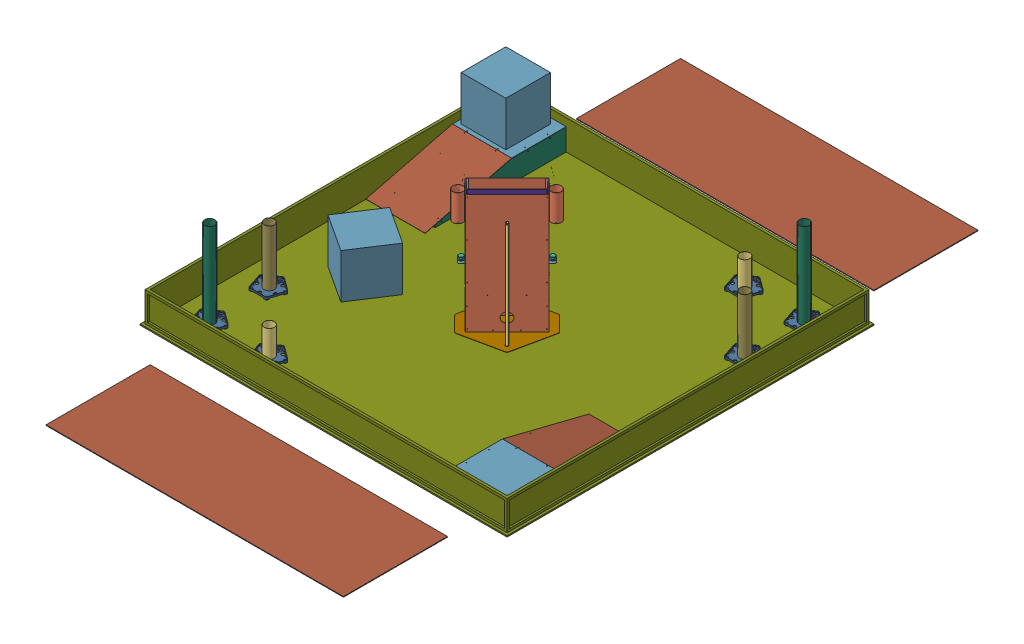
SolidWorks assembly FIELD, configuration Default. Lengths in mm.
Overall size (3759.2 1387.73 6502.4).
321 component instances, 51 part files, 0 mates.
Components (placement in the parent):
- pentagon_foot-1: pentagon_foot [Default] at (988.2301 6.35 -1420.0673) x (-0.309017 0 -0.951057) z (0.951057 0 -0.309017) size (62.1 10.92 43.36)
- 1in_ball_caster-1: 1in_ball_caster [Default] at (913.384 12.7 -1651.3697) x (-0.809017 0 0.587785) z (-0.587785 0 -0.809017) size (25.4 25.4 25.4)
- pentagon_foot-2: pentagon_foot [Default] at (1034.3923 6.35 -1562.3639) x (-1 0 0) z (0 0 -1) size (62.1 10.92 43.36)
- 1in_ball_caster-2: 1in_ball_caster [Default] at (791.2819 12.7 -1562.6574) x (0.309017 0 0.951057) z (-0.951057 0 0.309017) size (25.4 25.4 25.4)
- pentagon_foot-3: pentagon_foot [Default] at (913.3251 6.35 -1650.2388) x (-0.309017 0 0.951057) z (-0.951057 0 -0.309017) size (62.1 10.92 43.36)
- pipe_-_30cm-1: pipe_-_30cm [Default] at (913.384 25.4 -1522.984) size (103.63 274.6 103.63)
- boss-extrude10_2_-1: boss-extrude10_2_ [Default] at (913.384 12.7 -1522.984) size (18.23 0.25 19.26)
- boss-extrude10_3_-1: boss-extrude10_3_ [Default] at (913.384 12.7 -1522.984) size (18.74 0.25 19.26)
- boss-extrude10_5_-1: boss-extrude10_5_ [Default] at (913.384 12.7 -1522.984) size (15.54 0.29 7.33)
- boss-extrude10_7_-1: boss-extrude10_7_ [Default] at (913.384 12.7 -1522.984) size (2.53 0.25 2.49)
- boss-extrude10_1_-1: boss-extrude10_1_ [Default] at (913.384 12.7 -1522.984) size (20.84 0.25 21.41)
- boss-extrude10_6_-1: boss-extrude10_6_ [Default] at (913.384 12.7 -1522.984) size (1.07 0.25 1.44)
- boss-extrude11-1: boss-extrude11 [Default] at (913.384 12.7 -1522.984) size (286.32 38.24 275.93)
- pentagon_foot-4: pentagon_foot [Default] at (792.3393 6.35 -1562.2519) x (0.809017 0 0.587785) z (-0.587785 0 0.809017) size (62.1 10.92 43.36)
- pentagon_foot-5: pentagon_foot [Default] at (838.6332 6.35 -1419.9981) x (0.809017 0 -0.587785) z (0.587785 0 0.809017) size (62.1 10.92 43.36)
- 1in_ball_caster-3: 1in_ball_caster [Default] at (988.8472 12.7 -1419.1178) x (0.309017 0 -0.951057) z (0.951057 0 0.309017) size (25.4 25.4 25.4)
- 1in_ball_caster-4: 1in_ball_caster [Default] at (837.9208 12.7 -1419.1178) size (25.4 25.4 25.4)
- 1in_ball_caster-5: 1in_ball_caster [Default] at (1035.4861 12.7 -1562.6574) x (-0.809017 0 -0.587785) z (0.587785 0 -0.809017) size (25.4 25.4 25.4)
- player_station-1: player_station [Default] at (1574.8 -12.7 3251.2) x (0 0 -1) z (1 0 0) size (1066.8 6.35 3048)
- pentagon_foot-6: pentagon_foot [Default] at (-1401.9757 6.35 874.0041) x (-1 0 0) z (0 0 -1) size (62.1 10.92 43.36)
- 1in_ball_caster-6: 1in_ball_caster [Default] at (-1645.0861 12.7 873.7106) x (0.309017 0 0.951057) z (-0.951057 0 0.309017) size (25.4 25.4 25.4)
- pentagon_foot-7: pentagon_foot [Default] at (-1523.0429 6.35 786.1292) x (-0.309017 0 0.951057) z (-0.951057 0 -0.309017) size (62.1 10.92 43.36)
- pipe_-_60cm-1: pipe_-_60cm [Default] at (-1522.984 25.4 913.384) size (103.63 574.6 103.63)
- boss-extrude10_2_-2: boss-extrude10_2_ [Default] at (-1522.984 12.7 913.384) size (18.23 0.25 19.26)
- boss-extrude10_4_-2: boss-extrude10_4_ [Default] at (-1522.984 12.7 913.384) size (58.22 0.4 40.75)
- boss-extrude10_3_-2: boss-extrude10_3_ [Default] at (-1522.984 12.7 913.384) size (18.74 0.25 19.26)
- boss-extrude10_5_-2: boss-extrude10_5_ [Default] at (-1522.984 12.7 913.384) size (15.54 0.29 7.33)
- boss-extrude10_7_-2: boss-extrude10_7_ [Default] at (-1522.984 12.7 913.384) size (2.53 0.25 2.49)
- boss-extrude10_1_-2: boss-extrude10_1_ [Default] at (-1522.984 12.7 913.384) size (20.84 0.25 21.41)
- boss-extrude10_6_-2: boss-extrude10_6_ [Default] at (-1522.984 12.7 913.384) size (1.07 0.25 1.44)
- boss-extrude11-2: boss-extrude11 [Default] at (-1522.984 12.7 913.384) size (286.32 38.24 275.93)
- pentagon_foot-8: pentagon_foot [Default] at (-1644.0287 6.35 874.1161) x (0.809017 0 0.587785) z (-0.587785 0 0.809017) size (62.1 10.92 43.36)
- pentagon_foot-9: pentagon_foot [Default] at (-1597.7348 6.35 1016.3699) x (0.809017 0 -0.587785) z (0.587785 0 0.809017) size (62.1 10.92 43.36)
- 1in_ball_caster-7: 1in_ball_caster [Default] at (-1447.5208 12.7 1017.2502) x (0.309017 0 -0.951057) z (0.951057 0 0.309017) size (25.4 25.4 25.4)
- 1in_ball_caster-8: 1in_ball_caster [Default] at (-1598.4472 12.7 1017.2502) size (25.4 25.4 25.4)
- 1in_ball_caster-9: 1in_ball_caster [Default] at (-1400.8819 12.7 873.7106) x (-0.809017 0 -0.587785) z (0.587785 0 -0.809017) size (25.4 25.4 25.4)
- pentagon_foot-10: pentagon_foot [Default] at (-1448.1379 6.35 1016.3007) x (-0.309017 0 -0.951057) z (0.951057 0 -0.309017) size (62.1 10.92 43.36)
- 1in_ball_caster-10: 1in_ball_caster [Default] at (-1522.984 12.7 784.9983) x (-0.809017 0 0.587785) z (-0.587785 0 -0.809017) size (25.4 25.4 25.4)
- player_station-2: player_station [Default] at (-1473.2 -12.7 -3251.2) x (0 0 1) z (-1 0 0) size (1066.8 6.35 3048)
- pentagon_foot-11: pentagon_foot [Default] at (1643.9923 6.35 -952.7639) x (-1 0 0) z (0 0 -1) size (62.1 10.92 43.36)
- 1in_ball_caster-11: 1in_ball_caster [Default] at (1400.8819 12.7 -953.0574) x (0.309017 0 0.951057) z (-0.951057 0 0.309017) size (25.4 25.4 25.4)
- pentagon_foot-12: pentagon_foot [Default] at (1522.9251 6.35 -1040.6388) x (-0.309017 0 0.951057) z (-0.951057 0 -0.309017) size (62.1 10.92 43.36)
- pipe_-_60cm-2: pipe_-_60cm [Default] at (1522.984 25.4 -913.384) size (103.63 574.6 103.63)
- boss-extrude10_2_-3: boss-extrude10_2_ [Default] at (1522.984 12.7 -913.384) size (18.23 0.25 19.26)
- boss-extrude10_4_-3: boss-extrude10_4_ [Default] at (1522.984 12.7 -913.384) size (58.22 0.4 40.75)
- boss-extrude10_3_-3: boss-extrude10_3_ [Default] at (1522.984 12.7 -913.384) size (18.74 0.25 19.26)
- boss-extrude10_5_-3: boss-extrude10_5_ [Default] at (1522.984 12.7 -913.384) size (15.54 0.29 7.33)
- boss-extrude10_7_-3: boss-extrude10_7_ [Default] at (1522.984 12.7 -913.384) size (2.53 0.25 2.49)
- boss-extrude10_1_-3: boss-extrude10_1_ [Default] at (1522.984 12.7 -913.384) size (20.84 0.25 21.41)
- boss-extrude10_6_-3: boss-extrude10_6_ [Default] at (1522.984 12.7 -913.384) size (1.07 0.25 1.44)
- boss-extrude11-3: boss-extrude11 [Default] at (1522.984 12.7 -913.384) size (286.32 38.24 275.93)
- pentagon_foot-13: pentagon_foot [Default] at (1401.9393 6.35 -952.6519) x (0.809017 0 0.587785) z (-0.587785 0 0.809017) size (62.1 10.92 43.36)
- pentagon_foot-14: pentagon_foot [Default] at (1448.2332 6.35 -810.3981) x (0.809017 0 -0.587785) z (0.587785 0 0.809017) size (62.1 10.92 43.36)
- 1in_ball_caster-12: 1in_ball_caster [Default] at (1598.4472 12.7 -809.5178) x (0.309017 0 -0.951057) z (0.951057 0 0.309017) size (25.4 25.4 25.4)
- 1in_ball_caster-13: 1in_ball_caster [Default] at (1447.5208 12.7 -809.5178) size (25.4 25.4 25.4)
- 1in_ball_caster-14: 1in_ball_caster [Default] at (1645.0861 12.7 -953.0574) x (-0.809017 0 -0.587785) z (0.587785 0 -0.809017) size (25.4 25.4 25.4)
- pentagon_foot-15: pentagon_foot [Default] at (1597.8301 6.35 -810.4673) x (-0.309017 0 -0.951057) z (0.951057 0 -0.309017) size (62.1 10.92 43.36)
- 1in_ball_caster-15: 1in_ball_caster [Default] at (1522.984 12.7 -1041.7697) x (-0.809017 0 0.587785) z (-0.587785 0 -0.809017) size (25.4 25.4 25.4)
- simple_robot_starting_size-1: simple_robot_starting_size [Default] at (-1554.8184 225.25 -1542.4588) size (457.2 457.2 457.2)
- pentagon_foot-16: pentagon_foot [Default] at (-1523.0429 6.35 1395.7292) x (-0.309017 0 0.951057) z (-0.951057 0 -0.309017) size (62.1 10.92 43.36)
- pipe_-_90cm-1: pipe_-_90cm [Default] at (-1522.984 25.4 1522.984) size (103.63 874.6 103.63)
- boss-extrude10_2_-4: boss-extrude10_2_ [Default] at (-1522.984 12.7 1522.984) size (18.23 0.25 19.26)
- boss-extrude10_4_-4: boss-extrude10_4_ [Default] at (-1522.984 12.7 1522.984) size (58.22 0.4 40.75)
- boss-extrude10_3_-4: boss-extrude10_3_ [Default] at (-1522.984 12.7 1522.984) size (18.74 0.25 19.26)
- boss-extrude10_5_-4: boss-extrude10_5_ [Default] at (-1522.984 12.7 1522.984) size (15.54 0.29 7.33)
- boss-extrude10_7_-4: boss-extrude10_7_ [Default] at (-1522.984 12.7 1522.984) size (2.53 0.25 2.49)
- boss-extrude10_1_-4: boss-extrude10_1_ [Default] at (-1522.984 12.7 1522.984) size (20.84 0.25 21.41)
- boss-extrude10_6_-4: boss-extrude10_6_ [Default] at (-1522.984 12.7 1522.984) size (1.07 0.25 1.44)
- boss-extrude11-4: boss-extrude11 [Default] at (-1522.984 12.7 1522.984) size (286.32 38.24 275.93)
- pentagon_foot-17: pentagon_foot [Default] at (-1644.0287 6.35 1483.7161) x (0.809017 0 0.587785) z (-0.587785 0 0.809017) size (62.1 10.92 43.36)
- pentagon_foot-18: pentagon_foot [Default] at (-1597.7348 6.35 1625.9699) x (0.809017 0 -0.587785) z (0.587785 0 0.809017) size (62.1 10.92 43.36)
- 1in_ball_caster-16: 1in_ball_caster [Default] at (-1447.5208 12.7 1626.8502) x (0.309017 0 -0.951057) z (0.951057 0 0.309017) size (25.4 25.4 25.4)
- 1in_ball_caster-17: 1in_ball_caster [Default] at (-1598.4472 12.7 1626.8502) size (25.4 25.4 25.4)
- 1in_ball_caster-18: 1in_ball_caster [Default] at (-1400.8819 12.7 1483.3106) x (-0.809017 0 -0.587785) z (0.587785 0 -0.809017) size (25.4 25.4 25.4)
- pentagon_foot-19: pentagon_foot [Default] at (-1448.1379 6.35 1625.9007) x (-0.309017 0 -0.951057) z (0.951057 0 -0.309017) size (62.1 10.92 43.36)
- 1in_ball_caster-19: 1in_ball_caster [Default] at (-1522.984 12.7 1394.5983) x (-0.809017 0 0.587785) z (-0.587785 0 -0.809017) size (25.4 25.4 25.4)
- pentagon_foot-20: pentagon_foot [Default] at (-1401.9757 6.35 1483.6041) x (-1 0 0) z (0 0 -1) size (62.1 10.92 43.36)
- 1in_ball_caster-20: 1in_ball_caster [Default] at (-1645.0861 12.7 1483.3106) x (0.309017 0 0.951057) z (-0.951057 0 0.309017) size (25.4 25.4 25.4)
- field_marking_v2-1: field_marking_v2 [Default] at origin size (3759.2 317.5 3759.2)
- simple_robot_starting_size-2: simple_robot_starting_size [Default] at (-1302.6345 228.6 216.2201) x (0 -1 0) z (-0.546944 0 0.837169) size (457.2 457.2 457.2)
- pentagon_foot-21: pentagon_foot [Default] at (1522.9251 6.35 -1650.2388) x (-0.309017 0 0.951057) z (-0.951057 0 -0.309017) size (62.1 10.92 43.36)
- pipe_-_90cm-2: pipe_-_90cm [Default] at (1522.984 25.4 -1522.984) size (103.63 874.6 103.63)
- boss-extrude10_2_-5: boss-extrude10_2_ [Default] at (1522.984 12.7 -1522.984) size (18.23 0.25 19.26)
- boss-extrude10_4_-5: boss-extrude10_4_ [Default] at (1522.984 12.7 -1522.984) size (58.22 0.4 40.75)
- boss-extrude10_3_-5: boss-extrude10_3_ [Default] at (1522.984 12.7 -1522.984) size (18.74 0.25 19.26)
- boss-extrude10_5_-5: boss-extrude10_5_ [Default] at (1522.984 12.7 -1522.984) size (15.54 0.29 7.33)
- boss-extrude10_7_-5: boss-extrude10_7_ [Default] at (1522.984 12.7 -1522.984) size (2.53 0.25 2.49)
- boss-extrude10_1_-5: boss-extrude10_1_ [Default] at (1522.984 12.7 -1522.984) size (20.84 0.25 21.41)
- boss-extrude10_6_-5: boss-extrude10_6_ [Default] at (1522.984 12.7 -1522.984) size (1.07 0.25 1.44)
- boss-extrude11-5: boss-extrude11 [Default] at (1522.984 12.7 -1522.984) size (286.32 38.24 275.93)
- pentagon_foot-22: pentagon_foot [Default] at (1401.9393 6.35 -1562.2519) x (0.809017 0 0.587785) z (-0.587785 0 0.809017) size (62.1 10.92 43.36)
- pentagon_foot-23: pentagon_foot [Default] at (1448.2332 6.35 -1419.9981) x (0.809017 0 -0.587785) z (0.587785 0 0.809017) size (62.1 10.92 43.36)
- 1in_ball_caster-21: 1in_ball_caster [Default] at (1598.4472 12.7 -1419.1178) x (0.309017 0 -0.951057) z (0.951057 0 0.309017) size (25.4 25.4 25.4)
- 1in_ball_caster-22: 1in_ball_caster [Default] at (1447.5208 12.7 -1419.1178) size (25.4 25.4 25.4)
- 1in_ball_caster-23: 1in_ball_caster [Default] at (1645.0861 12.7 -1562.6574) x (-0.809017 0 -0.587785) z (0.587785 0 -0.809017) size (25.4 25.4 25.4)
- pentagon_foot-24: pentagon_foot [Default] at (1597.8301 6.35 -1420.0673) x (-0.309017 0 -0.951057) z (0.951057 0 -0.309017) size (62.1 10.92 43.36)
- 1in_ball_caster-24: 1in_ball_caster [Default] at (1522.984 12.7 -1651.3697) x (-0.809017 0 0.587785) z (-0.587785 0 -0.809017) size (25.4 25.4 25.4)
- pentagon_foot-25: pentagon_foot [Default] at (1643.9923 6.35 -1562.3639) x (-1 0 0) z (0 0 -1) size (62.1 10.92 43.36)
- 1in_ball_caster-25: 1in_ball_caster [Default] at (1400.8819 12.7 -1562.6574) x (0.309017 0 0.951057) z (-0.951057 0 0.309017) size (25.4 25.4 25.4)
- 10-32x1000_shcs_hx-shcs_0_19-32-1: 10-32x1000_shcs_hx-shcs_0_19-32 [Default] at (-227.9189 968.2 209.9584) x (0.707107 0 -0.707107) z (0.270008 -0.924225 0.270008) size (30.23 7.94 7.94)
- 0_125_rivet-1: 0_125_rivet [Default] at (-167.1495 340.4348 44.6588) x (-0.927593 -0.275814 -0.251989) z (0.120714 0.417045 -0.900834) size (7.15 10.43 6.43)
- 0_125_rivet-2: 0_125_rivet [Default] at (211.8083 17.986 -211.8083) x (0.421492 -0.802925 0.421492) z (0.567754 0.59608 0.567754) size (7.15 10.43 6.43)
- ug_bottom-1: ug_bottom [Default] at (252.1656 925.4006 -252.1656) x (0.707107 0 0.707107) z (-0.707107 0 0.707107) size (101.6 12 101.6)
- 0_125_rivet-3: 0_125_rivet [Default] at (205.8442 1234.9 -223.8048) x (0.342629 0.874764 0.342629) z (-0.618551 0.48455 -0.618551) size (7.15 10.43 6.43)
- pipe_-_30cm_center_goal-1: pipe_-_30cm_center_goal [Default] at (252.1656 925.4006 -252.1656) x (0.707107 0 -0.707107) z (0.707107 0 0.707107) size (103.63 274.6 103.63)
- 0_125_rivet-4: 0_125_rivet [Default] at (223.8048 1234.9 -205.8442) x (0.342629 0.874764 0.342629) z (-0.618551 0.48455 -0.618551) size (7.15 10.43 6.43)
- curved_backboard_formed-1: curved_backboard_formed [Default] at (252.1656 1171.425 -252.1656) x (0.707107 0 0.707107) z (-0.707107 0 0.707107) size (90.88 168.28 49.85)
- 0_125_rivet-5: 0_125_rivet [Default] at (285.0872 931.4006 -219.244) x (-0.342629 0.874764 0.342629) z (0.618551 0.48455 -0.618551) size (7.15 10.43 6.43)
- backboard_clip_spacer-1: backboard_clip_spacer [Default] at (216.2446 1234.9 -216.2446) x (0.707107 0 0.707107) z (-0.707107 0 0.707107) size (50.8 25.4 6)
- 0_125_rivet-6: 0_125_rivet [Default] at (219.244 931.4006 -285.0872) x (-0.07956 -0.99365 0.07956) z (0.702617 -0.112515 -0.702617) size (7.15 10.43 6.43)
- backboard_clip-1: backboard_clip [Default] at (212.0019 1222.2 -212.0019) x (0.707107 0 0.707107) z (-0.707107 0 0.707107) size (50.8 50.8 6)
- 0_125_rivet-7: 0_125_rivet [Default] at (-274.5444 1196.8 134.0573) x (-0.103977 -0.98913 0.103977) z (0.69942 -0.147045 -0.69942) size (7.15 10.43 6.43)
- cut-revolve4-26359-1: cut-revolve4-26359 [Default] at (-10.5967 5.286 133.0874) x (-0.707107 0 0.707107) z (-0.707107 0 -0.707107) size (9.53 4.54 11)
- revolve2-28113-1: revolve2-28113 [Default] at (-10.5967 5.286 133.0874) x (-0.707107 0 0.707107) z (-0.707107 0 -0.707107) size (9.57 0.43 9.57)
- bracket_90_-_bolt_bottom-1: bracket_90_-_bolt_bottom [Default] at (8.9803 30.686 134.7038) x (0 -1 0) z (0.707107 0 -0.707107) size (27.69 27.69 25.4)
- floor_plate-1: floor_plate [Default] x (-0.707107 0 0.707107) z (-0.707107 0 -0.707107) size (762 3 713.05)
- 0_125_rivet-8: 0_125_rivet [Default] at (211.8083 453.85 -211.8083) x (-0.568301 -0.595036 -0.568301) z (0.420754 -0.803699 0.420754) size (7.15 10.43 6.43)
- 10-32_x_0_375_bhcs-1: 10-32_x_0_375_bhcs [Default] at (133.0874 0 -10.5967) x (-0.978716 0 0.20522) z (0.20522 0 0.978716) size (9.17 12.09 9.17)
- 0_125_rivet-9: 0_125_rivet [Default] at (134.0573 28.4 -274.5444) x (-0.171866 0.970012 0.171866) z (-0.685902 -0.243056 0.685902) size (7.15 10.43 6.43)
- 0_125_rivet-10: 0_125_rivet [Default] at (-1.5985 17.986 142.0856) x (0.171866 0.970012 -0.171866) z (0.685902 -0.243056 -0.685902) size (7.15 10.43 6.43)
- center_pivot_plate-1: center_pivot_plate [Default] at (0 -16.97 0) x (-0.707107 0 0.707107) z (-0.707107 0 -0.707107) size (152.4 3 152.4)
- 0_125_rivet-11: 0_125_rivet [Default] at (-211.8083 428.45 211.8083) x (-0.171866 -0.970012 -0.171866) z (-0.685902 0.243056 -0.685902) size (7.15 10.43 6.43)
- cut-revolve4-26359-2: cut-revolve4-26359 [Default] at (200.6868 5.286 -200.6868) x (-0.707107 0 0.707107) z (-0.707107 0 -0.707107) size (9.53 4.54 11)
- revolve2-28113-2: revolve2-28113 [Default] at (200.6868 5.286 -200.6868) x (-0.707107 0 0.707107) z (-0.707107 0 -0.707107) size (9.57 0.43 9.57)
- bracket_90-1: bracket_90 [Default] at (-31.7884 309.4652 175.4725) x (-0.353553 0.866025 0.353553) z (-0.612372 -0.5 0.612372) size (27.69 27.69 25.4)
- 0_125_rivet-12: 0_125_rivet [Default] at (274.5444 441.15 -134.0573) x (-0.421492 -0.802925 0.421492) z (-0.567754 0.59608 0.567754) size (7.15 10.43 6.43)
- 10-32x1250_shcs-1: 10-32x1250_shcs [Default] at (209.9225 968.2 -227.883) x (0 1 0) z (-0.707107 0 -0.707107) size (7.82 36.53 7.82)
- 0_125_rivet-13: 0_125_rivet [Default] at (44.6588 340.4348 -167.1495) x (0.765875 -0.485006 -0.422143) z (0.537062 0.121528 0.834743) size (7.15 10.43 6.43)
- 0_125_rivet-14: 0_125_rivet [Default] at (30.0998 326.8138 -170.587) x (-0.171866 0.970012 0.171866) z (-0.685902 -0.243056 0.685902) size (7.15 10.43 6.43)
- 0_125_rivet-15: 0_125_rivet [Default] at (-211.8083 238.5265 211.8083) x (0.171866 0.970012 0.171866) z (0.685902 -0.243056 0.685902) size (7.15 10.43 6.43)
- 0_125_rivet-16: 0_125_rivet [Default] at (-202.8281 1171.4 220.7886) x (-0.171866 -0.970012 -0.171866) z (-0.685902 0.243056 -0.685902) size (7.15 10.43 6.43)
- bracket_90_-_bolt_bottom-2: bracket_90_-_bolt_bottom [Default] at (-8.9803 30.686 -134.7038) x (0 -1 0) z (-0.707107 0 0.707107) size (27.69 27.69 25.4)
- splitter_ramp_v2-1: splitter_ramp_v2 [Default] at (0 3 0) x (0.707107 0 -0.707107) z (0.707107 0 0.707107) size (609.6 428.43 203.2)
- cut-revolve4-26359-3: cut-revolve4-26359 [Default] at (188.6971 968.2 -206.6576) x (-0.653525 -0.381849 -0.653525) z (-0.270008 0.924225 -0.270008) size (9.53 4.54 11)
- revolve2-28113-3: revolve2-28113 [Default] at (188.6971 968.2 -206.6576) x (-0.653525 -0.381849 -0.653525) z (-0.270008 0.924225 -0.270008) size (9.57 0.43 9.57)
- 0_125_rivet-17: 0_125_rivet [Default] at (134.0573 441.15 -274.5444) x (-0.171866 0.970012 0.171866) z (-0.685902 -0.243056 0.685902) size (7.15 10.43 6.43)
- 10-32_x_0_375_bhcs-2: 10-32_x_0_375_bhcs [Default] at (200.6868 0 -200.6868) x (-0.978716 0 0.20522) z (0.20522 0 0.978716) size (9.17 12.09 9.17)
- 0_125_rivet-18: 0_125_rivet [Default] at (134.0573 231.6 -274.5444) x (-0.171866 0.970012 0.171866) z (-0.685902 -0.243056 0.685902) size (7.15 10.43 6.43)
- 0_125_rivet-19: 0_125_rivet [Default] at (1.5985 17.986 -142.0856) x (-0.171866 0.970012 0.171866) z (-0.685902 -0.243056 0.685902) size (7.15 10.43 6.43)
- elevator_screw_1_25in-1: elevator_screw_1_25in [Default] at (0 -19.4592 0) x (-0.707107 0 0.707107) z (-0.707107 0 -0.707107) size (25.6 31.75 25.6)
- 0_125_rivet-20: 0_125_rivet [Default] at (-211.8083 453.85 211.8083) x (-0.171866 -0.970012 -0.171866) z (-0.685902 0.243056 -0.685902) size (7.15 10.43 6.43)
- cut-revolve4-26359-4: cut-revolve4-26359 [Default] at (-200.6868 5.286 200.6868) x (-0.707107 0 0.707107) z (-0.707107 0 -0.707107) size (9.53 4.54 11)
- revolve2-28113-4: revolve2-28113 [Default] at (-200.6868 5.286 200.6868) x (-0.707107 0 0.707107) z (-0.707107 0 -0.707107) size (9.57 0.43 9.57)
- bracket_90-2: bracket_90 [Default] at (-159.9182 322.1652 16.2341) x (-0.353553 0.866025 0.353553) z (0.612372 0.5 -0.612372) size (27.69 27.69 25.4)
- pipe_diverter-1: pipe_diverter [Default] at (202.3033 333.2 -202.3033) x (-0.707107 0 0.707107) z (-0.707107 0 -0.707107) size (25.4 266.7 25.4)
- 0_125_rivet-21: 0_125_rivet [Default] at (-134.0573 441.15 274.5444) x (0.171866 0.970012 -0.171866) z (0.685902 -0.243056 -0.685902) size (7.15 10.43 6.43)
- 10-32x1000_shcs_hx-shcs_0_19-32-2: 10-32x1000_shcs_hx-shcs_0_19-32 [Default] at (227.9189 968.2 -209.9584) x (-0.707107 0 0.707107) z (-0.707107 0 -0.707107) size (30.23 7.94 7.94)
- 0_125_rivet-22: 0_125_rivet [Default] at (167.1495 340.4348 -44.6588) x (0.765875 -0.485006 -0.422143) z (0.537062 0.121528 0.834743) size (7.15 10.43 6.43)
- 0_125_rivet-23: 0_125_rivet [Default] at (-170.587 326.8138 30.0998) x (-0.171866 0.970012 0.171866) z (-0.685902 -0.243056 0.685902) size (7.15 10.43 6.43)
- 0_125_rivet-24: 0_125_rivet [Default] at (-211.8083 225.8265 211.8083) x (0.171866 0.970012 0.171866) z (0.685902 -0.243056 0.685902) size (7.15 10.43 6.43)
- 0_125_rivet-25: 0_125_rivet [Default] at (-202.8281 866.6 220.7886) x (-0.171866 -0.970012 -0.171866) z (-0.685902 0.243056 -0.685902) size (7.15 10.43 6.43)
- bracket_90_-_bolt_bottom-3: bracket_90_-_bolt_bottom [Default] at (-152.6644 30.686 8.9803) x (0 -1 0) z (-0.707107 0 0.707107) size (27.69 27.69 25.4)
- upper_cross_brace-1: upper_cross_brace [Default] at (-2.1213 1019 2.1213) x (0.707107 0 -0.707107) z (-0.707107 0 -0.707107) size (597.6 355.6 44.8)
- cut-revolve4-26359-5: cut-revolve4-26359 [Default] at (-210.9243 968.2 192.9638) x (0.653525 0.381849 0.653525) z (-0.270008 0.924225 -0.270008) size (9.53 4.54 11)
- revolve2-28113-5: revolve2-28113 [Default] at (-210.9243 968.2 192.9638) x (0.653525 0.381849 0.653525) z (-0.270008 0.924225 -0.270008) size (9.57 0.43 9.57)
- 0_125_rivet-26: 0_125_rivet [Default] at (134.0573 818.975 -274.5444) x (-0.171866 0.970012 0.171866) z (-0.685902 -0.243056 0.685902) size (7.15 10.43 6.43)
- 10-32_x_0_375_bhcs-3: 10-32_x_0_375_bhcs [Default] at (10.5967 0 -133.0874) x (-0.978716 0 0.20522) z (0.20522 0 0.978716) size (9.17 12.09 9.17)
- 0_125_rivet-27: 0_125_rivet [Default] at (211.8083 238.5265 -211.8083) x (-0.568301 -0.595036 -0.568301) z (0.420754 -0.803699 0.420754) size (7.15 10.43 6.43)
- 0_125_rivet-28: 0_125_rivet [Default] at (-142.0856 17.986 1.5985) x (-0.171866 0.970012 0.171866) z (-0.685902 -0.243056 0.685902) size (7.15 10.43 6.43)
- revolve2-15193-1: revolve2-15193 [Default] at (0 3 0) x (-0.707107 0 0.707107) z (-0.707107 0 -0.707107) size (11.24 0.56 11.25)
- cut-revolve4-44804-1: cut-revolve4-44804 [Default] at (0 3 0) x (-0.707107 0 0.707107) z (-0.707107 0 -0.707107) size (11.11 5.35 12.83)
- 0_125_rivet-29: 0_125_rivet [Default] at (-211.8083 441.15 211.8083) x (-0.171866 -0.970012 -0.171866) z (-0.685902 0.243056 -0.685902) size (7.15 10.43 6.43)
- cut-revolve4-26359-6: cut-revolve4-26359 [Default] at (10.5967 5.286 -133.0874) x (-0.707107 0 0.707107) z (-0.707107 0 -0.707107) size (9.53 4.54 11)
- revolve2-28113-6: revolve2-28113 [Default] at (10.5967 5.286 -133.0874) x (-0.707107 0 0.707107) z (-0.707107 0 -0.707107) size (9.57 0.43 9.57)
- bracket_90-3: bracket_90 [Default] at (31.7884 309.4652 -175.4725) x (0.353553 0.866025 -0.353553) z (0.612372 -0.5 -0.612372) size (27.69 27.69 25.4)
- pipe_diverter-2: pipe_diverter [Default] at (-202.3033 333.2 202.3033) x (0.707107 0 -0.707107) z (0.707107 0 0.707107) size (25.4 266.7 25.4)
- 0_125_rivet-30: 0_125_rivet [Default] at (-134.0573 818.975 274.5444) x (0.171866 0.970012 -0.171866) z (0.685902 -0.243056 -0.685902) size (7.15 10.43 6.43)
- 10-32x1250_shcs-2: 10-32x1250_shcs [Default] at (-209.9225 968.2 227.883) x (0.653525 0.381849 0.653525) z (0.270008 -0.924225 0.270008) size (7.82 36.53 7.82)
- 0_125_rivet-31: 0_125_rivet [Default] at (-44.6588 340.4348 167.1495) x (-0.927593 -0.275814 -0.251989) z (0.120714 0.417045 -0.900834) size (7.15 10.43 6.43)
- 0_125_rivet-32: 0_125_rivet [Default] at (-30.0998 326.8138 170.587) x (0.421492 0.802925 -0.421492) z (0.567754 -0.59608 -0.567754) size (7.15 10.43 6.43)
- 0_125_rivet-33: 0_125_rivet [Default] at (-211.8083 213.1265 211.8083) x (0.171866 0.970012 0.171866) z (0.685902 -0.243056 0.685902) size (7.15 10.43 6.43)
- 0_125_rivet-34: 0_125_rivet [Default] at (202.8281 1171.4 -220.7886) x (-0.568301 -0.595036 -0.568301) z (0.420754 -0.803699 0.420754) size (7.15 10.43 6.43)
- bracket_90_-_bolt_bottom-4: bracket_90_-_bolt_bottom [Default] at (152.6644 30.686 -8.9803) x (0 -1 0) z (0.707107 0 -0.707107) size (27.69 27.69 25.4)
- front_panel_v2-1: front_panel_v2 [Default] at (73.9614 612.6 73.9614) x (-0.707107 0 0.707107) z (-0.707107 0 -0.707107) size (604.84 1219.2 3)
- cut-revolve4-26359-7: cut-revolve4-26359 [Default] at (-188.6971 968.2 206.6576) x (0.653525 0.381849 0.653525) z (-0.270008 0.924225 -0.270008) size (9.53 4.54 11)
- revolve2-28113-7: revolve2-28113 [Default] at (-188.6971 968.2 206.6576) x (0.653525 0.381849 0.653525) z (-0.270008 0.924225 -0.270008) size (9.57 0.43 9.57)
- 0_125_rivet-35: 0_125_rivet [Default] at (134.0573 1196.8 -274.5444) x (-0.171866 0.970012 0.171866) z (-0.685902 -0.243056 0.685902) size (7.15 10.43 6.43)
- 10-32_x_0_375_bhcs-4: 10-32_x_0_375_bhcs [Default] at (-133.0874 0 10.5967) x (-0.978716 0 0.20522) z (0.20522 0 0.978716) size (9.17 12.09 9.17)
- 0_125_rivet-36: 0_125_rivet [Default] at (211.8083 225.8265 -211.8083) x (-0.568301 -0.595036 -0.568301) z (0.420754 -0.803699 0.420754) size (7.15 10.43 6.43)
- 0_125_rivet-37: 0_125_rivet [Default] at (274.5444 28.4 -134.0573) x (-0.421492 -0.802925 0.421492) z (-0.567754 0.59608 0.567754) size (7.15 10.43 6.43)
- pipe_v4-1: pipe_v4 [Default] at (134.5565 482.9183 134.5565) x (0.697656 0.162946 0.697656) z (-0.707107 0 0.707107) size (25.4 974.72 25.4)
- 0_125_rivet-38: 0_125_rivet [Default] at (-274.5444 441.15 134.0573) x (-0.103977 -0.98913 0.103977) z (0.69942 -0.147045 -0.69942) size (7.15 10.43 6.43)
- cut-revolve4-26359-8: cut-revolve4-26359 [Default] at (-133.0874 5.286 10.5967) x (-0.707107 0 0.707107) z (-0.707107 0 -0.707107) size (9.53 4.54 11)
- revolve2-28113-8: revolve2-28113 [Default] at (-133.0874 5.286 10.5967) x (-0.707107 0 0.707107) z (-0.707107 0 -0.707107) size (9.57 0.43 9.57)
- bracket_90_-_bolt_bottom-5: bracket_90_-_bolt_bottom [Default] at (-202.3033 30.686 220.2638) x (0 -1 0) z (0.707107 0 0.707107) size (27.69 27.69 25.4)
- side_panel_upper-1: side_panel_upper [Default] at (211.2835 612.6 -211.2835) x (-0.707107 0 -0.707107) z (0.707107 0 -0.707107) size (203.2 806.45 25.4)
- 0_125_rivet-39: 0_125_rivet [Default] at (-134.0573 1196.8 274.5444) x (0.171866 0.970012 -0.171866) z (0.685902 -0.243056 -0.685902) size (7.15 10.43 6.43)
- new_irbeacon_base-1: new_irbeacon_base [Default] at (-234.8899 582.6125 234.8899) x (0.707107 0 0.707107) z (0 1 0) size (68.63 60.17 23.81)
- new_irbeacon_top-1: new_irbeacon_top [Default] at (-234.8899 582.6125 234.8899) x (0.707107 0 0.707107) z (0 1 0) size (68.35 60.04 25.42)
- 0_125_rivet-40: 0_125_rivet [Default] at (211.8083 428.45 -211.8083) x (-0.568301 -0.595036 -0.568301) z (0.420754 -0.803699 0.420754) size (7.15 10.43 6.43)
- 0_125_rivet-41: 0_125_rivet [Default] at (170.587 326.8138 -30.0998) x (0.421492 0.802925 -0.421492) z (0.567754 -0.59608 -0.567754) size (7.15 10.43 6.43)
- 0_125_rivet-42: 0_125_rivet [Default] at (-274.5444 231.6 134.0573) x (-0.171866 0.970012 0.171866) z (-0.685902 -0.243056 0.685902) size (7.15 10.43 6.43)
- 0_125_rivet-43: 0_125_rivet [Default] at (202.8281 866.6 -220.7886) x (-0.568301 -0.595036 -0.568301) z (0.420754 -0.803699 0.420754) size (7.15 10.43 6.43)
- ball_tray_v4-1: ball_tray_v4 [Default] at (-37.1563 968.2 -32.8897) x (-0.707107 0 0.707107) z (-0.707107 0 -0.707107) size (590.55 12 115.57)
- 0_125_rivet-44: 0_125_rivet [Default] at (-134.0573 28.4 274.5444) x (-0.421492 -0.802925 0.421492) z (-0.567754 0.59608 0.567754) size (7.15 10.43 6.43)
- front_panel_v2-2: front_panel_v2 [Default] at (-71.842 612.6 -71.842) x (-0.707107 0 0.707107) z (-0.707107 0 -0.707107) size (604.84 1219.2 3)
- cut-revolve4-26359-9: cut-revolve4-26359 [Default] at (210.9243 968.2 -192.9638) x (-0.653525 -0.381849 -0.653525) z (-0.270008 0.924225 -0.270008) size (9.53 4.54 11)
- revolve2-28113-9: revolve2-28113 [Default] at (210.9243 968.2 -192.9638) x (-0.653525 -0.381849 -0.653525) z (-0.270008 0.924225 -0.270008) size (9.57 0.43 9.57)
- 0_125_rivet-45: 0_125_rivet [Default] at (274.5444 1196.8 -134.0573) x (-0.421492 -0.802925 0.421492) z (-0.567754 0.59608 0.567754) size (7.15 10.43 6.43)
- 10-32_x_0_375_bhcs-5: 10-32_x_0_375_bhcs [Default] at (-200.6868 0 200.6868) x (-0.978716 0 0.20522) z (0.20522 0 0.978716) size (9.17 12.09 9.17)
- 0_125_rivet-46: 0_125_rivet [Default] at (211.8083 213.1265 -211.8083) x (-0.568301 -0.595036 -0.568301) z (0.420754 -0.803699 0.420754) size (7.15 10.43 6.43)
- 0_125_rivet-47: 0_125_rivet [Default] at (274.5444 231.6 -134.0573) x (-0.421492 -0.802925 0.421492) z (-0.567754 0.59608 0.567754) size (7.15 10.43 6.43)
- ug_bottom-2: ug_bottom [Default] at (-252.1656 925.4006 252.1656) x (-0.707107 0 -0.707107) z (0.707107 0 -0.707107) size (101.6 12 101.6)
- 0_125_rivet-48: 0_125_rivet [Default] at (-205.8442 1234.9 223.8048) x (-0.342629 0.874764 -0.342629) z (0.618551 0.48455 0.618551) size (7.15 10.43 6.43)
- pipe_-_30cm_center_goal-2: pipe_-_30cm_center_goal [Default] at (-252.1656 925.4006 252.1656) x (-0.707107 0 0.707107) z (-0.707107 0 -0.707107) size (103.63 274.6 103.63)
- 0_125_rivet-49: 0_125_rivet [Default] at (-223.8048 1234.9 205.8442) x (-0.342629 0.874764 -0.342629) z (0.618551 0.48455 0.618551) size (7.15 10.43 6.43)
- curved_backboard_formed-2: curved_backboard_formed [Default] at (-252.1656 1171.425 252.1656) x (-0.707107 0 -0.707107) z (0.707107 0 -0.707107) size (90.88 168.28 49.85)
- 0_125_rivet-50: 0_125_rivet [Default] at (-285.0872 931.4006 219.244) x (0.342629 0.874764 -0.342629) z (-0.618551 0.48455 0.618551) size (7.15 10.43 6.43)
- backboard_clip_spacer-2: backboard_clip_spacer [Default] at (-216.2446 1234.9 216.2446) x (-0.707107 0 -0.707107) z (0.707107 0 -0.707107) size (50.8 25.4 6)
- 0_125_rivet-51: 0_125_rivet [Default] at (-219.244 931.4006 285.0872) x (0.07956 -0.99365 -0.07956) z (-0.702617 -0.112515 0.702617) size (7.15 10.43 6.43)
- backboard_clip-2: backboard_clip [Default] at (-212.0019 1222.2 212.0019) x (-0.707107 0 -0.707107) z (0.707107 0 -0.707107) size (50.8 50.8 6)
- 0_125_rivet-52: 0_125_rivet [Default] at (-274.5444 818.975 134.0573) x (-0.103977 -0.98913 0.103977) z (0.69942 -0.147045 -0.69942) size (7.15 10.43 6.43)
- cut-revolve4-26359-10: cut-revolve4-26359 [Default] at (133.0874 5.286 -10.5967) x (-0.707107 0 0.707107) z (-0.707107 0 -0.707107) size (9.53 4.54 11)
- revolve2-28113-10: revolve2-28113 [Default] at (133.0874 5.286 -10.5967) x (-0.707107 0 0.707107) z (-0.707107 0 -0.707107) size (9.57 0.43 9.57)
- bracket_90_-_bolt_bottom-6: bracket_90_-_bolt_bottom [Default] at (202.3033 30.686 -220.2638) x (0 -1 0) z (-0.707107 0 -0.707107) size (27.69 27.69 25.4)
- side_panel_upper-2: side_panel_upper [Default] at (-211.2835 612.6 211.2835) x (0.707107 0 0.707107) z (-0.707107 0 0.707107) size (203.2 806.45 25.4)
- 0_125_rivet-53: 0_125_rivet [Default] at (-134.0573 231.6 274.5444) x (-0.421492 -0.802925 0.421492) z (-0.567754 0.59608 0.567754) size (7.15 10.43 6.43)
- new_irbeacon_base-2: new_irbeacon_base [Default] at (234.8899 582.6125 -234.8899) x (-0.707107 0 -0.707107) z (0 1 0) size (68.63 60.17 23.81)
- new_irbeacon_top-2: new_irbeacon_top [Default] at (234.8899 582.6125 -234.8899) x (-0.707107 0 -0.707107) z (0 1 0) size (68.35 60.04 25.42)
- 0_125_rivet-54: 0_125_rivet [Default] at (211.8083 441.15 -211.8083) x (-0.568301 -0.595036 -0.568301) z (0.420754 -0.803699 0.420754) size (7.15 10.43 6.43)
- 10-32_x_0_375_bhcs-6: 10-32_x_0_375_bhcs [Default] at (-10.5967 0 133.0874) x (-0.978716 0 0.20522) z (0.20522 0 0.978716) size (9.17 12.09 9.17)
- 0_125_rivet-55: 0_125_rivet [Default] at (-274.5444 28.4 134.0573) x (-0.171866 0.970012 0.171866) z (-0.685902 -0.243056 0.685902) size (7.15 10.43 6.43)
- 0_125_rivet-56: 0_125_rivet [Default] at (142.0856 17.986 -1.5985) x (0.171866 0.970012 -0.171866) z (0.685902 -0.243056 -0.685902) size (7.15 10.43 6.43)
- pipe_v4-2: pipe_v4 [Default] at (-134.8712 482.9798 -134.8712) x (0.697762 -0.162036 0.697762) z (-0.707107 0 0.707107) size (25.4 974.72 25.4)
- 0_125_rivet-57: 0_125_rivet [Default] at (-211.8083 17.986 211.8083) x (0.171866 0.970012 0.171866) z (0.685902 -0.243056 0.685902) size (7.15 10.43 6.43)
- ball_tray_v4-2: ball_tray_v4 [Default] at (37.1563 968.2 32.8897) x (0.707107 0 -0.707107) z (0.707107 0 0.707107) size (590.55 12 115.57)
- bracket_90-4: bracket_90 [Default] at (159.9182 322.1652 -16.2341) x (0.353553 0.866025 -0.353553) z (-0.612372 0.5 0.612372) size (27.69 27.69 25.4)
- 0_125_rivet-58: 0_125_rivet [Default] at (274.5444 818.975 -134.0573) x (-0.421492 -0.802925 0.421492) z (-0.567754 0.59608 0.567754) size (7.15 10.43 6.43)
- pentagon_foot-26: pentagon_foot [Default] at (-838.5379 6.35 1625.9007) x (-0.309017 0 -0.951057) z (0.951057 0 -0.309017) size (62.1 10.92 43.36)
- 1in_ball_caster-26: 1in_ball_caster [Default] at (-913.384 12.7 1394.5983) x (-0.809017 0 0.587785) z (-0.587785 0 -0.809017) size (25.4 25.4 25.4)
- pentagon_foot-27: pentagon_foot [Default] at (-792.3757 6.35 1483.6041) x (-1 0 0) z (0 0 -1) size (62.1 10.92 43.36)
- 1in_ball_caster-27: 1in_ball_caster [Default] at (-1035.4861 12.7 1483.3106) x (0.309017 0 0.951057) z (-0.951057 0 0.309017) size (25.4 25.4 25.4)
- pentagon_foot-28: pentagon_foot [Default] at (-913.4429 6.35 1395.7292) x (-0.309017 0 0.951057) z (-0.951057 0 -0.309017) size (62.1 10.92 43.36)
- pipe_-_30cm-2: pipe_-_30cm [Default] at (-913.384 25.4 1522.984) size (103.63 274.6 103.63)
- boss-extrude10_2_-6: boss-extrude10_2_ [Default] at (-913.384 12.7 1522.984) size (18.23 0.25 19.26)
- boss-extrude10_4_-6: boss-extrude10_4_ [Default] at (-913.384 12.7 1522.984) size (58.22 0.4 40.75)
- boss-extrude10_3_-6: boss-extrude10_3_ [Default] at (-913.384 12.7 1522.984) size (18.74 0.25 19.26)
- boss-extrude10_5_-6: boss-extrude10_5_ [Default] at (-913.384 12.7 1522.984) size (15.54 0.29 7.33)
- boss-extrude10_7_-6: boss-extrude10_7_ [Default] at (-913.384 12.7 1522.984) size (2.53 0.25 2.49)
- boss-extrude10_1_-6: boss-extrude10_1_ [Default] at (-913.384 12.7 1522.984) size (20.84 0.25 21.41)
- boss-extrude10_6_-6: boss-extrude10_6_ [Default] at (-913.384 12.7 1522.984) size (1.07 0.25 1.44)
- boss-extrude11-6: boss-extrude11 [Default] at (-913.384 12.7 1522.984) size (286.32 38.24 275.93)
- pentagon_foot-29: pentagon_foot [Default] at (-1034.4287 6.35 1483.7161) x (0.809017 0 0.587785) z (-0.587785 0 0.809017) size (62.1 10.92 43.36)
- pentagon_foot-30: pentagon_foot [Default] at (-988.1348 6.35 1625.9699) x (0.809017 0 -0.587785) z (0.587785 0 0.809017) size (62.1 10.92 43.36)
- 1in_ball_caster-28: 1in_ball_caster [Default] at (-837.9208 12.7 1626.8502) x (0.309017 0 -0.951057) z (0.951057 0 0.309017) size (25.4 25.4 25.4)
- 1in_ball_caster-29: 1in_ball_caster [Default] at (-988.8472 12.7 1626.8502) size (25.4 25.4 25.4)
- 1in_ball_caster-30: 1in_ball_caster [Default] at (-791.2819 12.7 1483.3106) x (-0.809017 0 -0.587785) z (0.587785 0 -0.809017) size (25.4 25.4 25.4)
- 10-32_thin_nylock_nut-1: 10-32_thin_nylock_nut [Default] at (1374.775 219.964 1282.954) x (0.837169 0 0.546944) z (0.546944 0 -0.837169) size (11 4.37 9.53)
- 10-32_x_0_75_shcs-1: 10-32_x_0_75_shcs [Default] at (1667.575 25.5919 546.8122) x (0 -1 0) z (0 0 -1) size (7.94 23.88 7.94)
- ramp_rib_v4-1: ramp_rib_v4 [Default] at (1828.8 0 1828.8) x (-1 0 0) z (0 0 -1) size (12 222.25 868.16)
- 10-32_thin_nylock_nut-2: 10-32_thin_nylock_nut [Default] at (1236.661 25.5919 546.8122) x (0 1 0) z (0 0 -1) size (11 4.37 9.53)
- 0_125_rivet-59: 0_125_rivet [Default] at (1692.275 216.8496 1257.7368) x (-1 0 0) z (0 -0.243056 -0.970012) size (7.15 10.43 6.43)
- 10-32_x_0_375_bhcs-7: 10-32_x_0_375_bhcs [Default] at (1692.275 225.25 1282.954) x (-1 0 0) z (0 0 -1) size (9.17 12.09 9.17)
- ramp-1: ramp [Default] at (1525.5875 111.125 826.5103) x (-1 0 0) z (0 -0.243056 -0.970012) size (606.42 3 914.4)
- 10-32_thin_nylock_nut-3: 10-32_thin_nylock_nut [Default] at (1681.861 142.8905 1014.9401) x (0 1 0) z (0 0 -1) size (11 4.37 9.53)
- 10-32_x_0_75_shcs-2: 10-32_x_0_75_shcs [Default] at (1667.575 142.8905 1014.9401) x (0 -1 0) z (0 0 -1) size (7.94 23.88 7.94)
- bracket_90_-_bolt_bottom-7: bracket_90_-_bolt_bottom [Default] at (1707.261 160.5139 1023.6169) x (-1 0 0) z (0 0.243056 0.970012) size (27.69 27.69 25.4)
- 0_125_rivet-60: 0_125_rivet [Default] at (1374.775 216.8496 1257.7368) x (-1 0 0) z (0 -0.243056 -0.970012) size (7.15 10.43 6.43)
- 10-32_x_0_75_shcs-3: 10-32_x_0_75_shcs [Default] at (1222.375 25.5919 546.8122) x (0 -1 0) z (0 0 -1) size (7.94 23.88 7.94)
- bracket_90_-_bolt_bottom-8: bracket_90_-_bolt_bottom [Default] at (1262.061 222.25 1447.8) x (-1 0 0) z (0 0 1) size (27.69 27.69 25.4)
- 10-32_thin_nylock_nut-4: 10-32_thin_nylock_nut [Default] at (1681.861 25.5919 546.8122) x (0 1 0) z (0 0 -1) size (11 4.37 9.53)
- 0_125_rivet-61: 0_125_rivet [Default] at (1694.561 155.237 1011.8465) x (-1 0 0) z (0 -0.243056 -0.970012) size (7.15 10.43 6.43)
- bracket_90_-_bolt_bottom-9: bracket_90_-_bolt_bottom [Default] at (1707.261 43.2153 555.4889) x (-1 0 0) z (0 0.243056 0.970012) size (27.69 27.69 25.4)
- 0_125_rivet-62: 0_125_rivet [Default] at (1249.361 219.9922 1435.1) x (-1 0 0) z (0 0 -1) size (7.15 10.43 6.43)
- 10-32_x_0_75_shcs-4: 10-32_x_0_75_shcs [Default] at (1222.375 142.8905 1014.9401) x (0 -1 0) z (0 0 -1) size (7.94 23.88 7.94)
- bracket_90_-_bolt_bottom-10: bracket_90_-_bolt_bottom [Default] at (1262.061 222.25 1676.4) x (-1 0 0) z (0 0 1) size (27.69 27.69 25.4)
- 10-32_thin_nylock_nut-5: 10-32_thin_nylock_nut [Default] at (1236.661 207.264 1435.1) x (0 1 0) z (0 0 -1) size (11 4.37 9.53)
- 0_125_rivet-63: 0_125_rivet [Default] at (1249.361 155.237 1011.8465) x (-1 0 0) z (0 -0.243056 -0.970012) size (7.15 10.43 6.43)
- bracket_15-1: bracket_15 [Default] at (1362.075 222.25 1295.654) x (0 0 -1) z (-1 0 0) size (50.63 8.86 25.4)
- folding_crate-1: folding_crate [Default] at (1828.8 222.25 1352.55) x (0 0 1) z (1 0 0) size (479.43 222.25 346.08)
- 0_125_rivet-64: 0_125_rivet [Default] at (1249.361 219.9922 1663.7) x (-1 0 0) z (0 0 -1) size (7.15 10.43 6.43)
- 10-32_x_0_75_shcs-5: 10-32_x_0_75_shcs [Default] at (1222.375 207.264 1435.1) x (0 -1 0) z (0 0 -1) size (7.94 23.88 7.94)
- bracket_90_-_bolt_bottom-11: bracket_90_-_bolt_bottom [Default] at (1262.061 160.5139 1023.6169) x (-1 0 0) z (0 0.243056 0.970012) size (27.69 27.69 25.4)
- 10-32_thin_nylock_nut-6: 10-32_thin_nylock_nut [Default] at (1236.661 207.264 1663.7) x (0 1 0) z (0 0 -1) size (11 4.37 9.53)
- 0_125_rivet-65: 0_125_rivet [Default] at (1249.361 37.9384 543.7185) x (-1 0 0) z (0 -0.243056 -0.970012) size (7.15 10.43 6.43)
- bracket_15-2: bracket_15 [Default] at (1679.575 222.25 1295.654) x (0 0 -1) z (-1 0 0) size (50.63 8.86 25.4)
- plateau_v2-1: plateau_v2 [Default] at (1525.5875 222.25 1549.4) x (-1 0 0) z (0 0 -1) size (606.42 3 558.8)
- 10-32_thin_nylock_nut-7: 10-32_thin_nylock_nut [Default] at (1692.275 219.964 1282.954) x (0.837169 0 0.546944) z (0.546944 0 -0.837169) size (11 4.37 9.53)
- 10-32_x_0_75_shcs-6: 10-32_x_0_75_shcs [Default] at (1222.375 207.264 1663.7) x (0 -1 0) z (0 0 -1) size (7.94 23.88 7.94)
- bracket_90_-_bolt_bottom-12: bracket_90_-_bolt_bottom [Default] at (1262.061 43.2153 555.4889) x (-1 0 0) z (0 0.243056 0.970012) size (27.69 27.69 25.4)
- 10-32_thin_nylock_nut-8: 10-32_thin_nylock_nut [Default] at (1236.661 142.8905 1014.9401) x (0 1 0) z (0 0 -1) size (11 4.37 9.53)
- 0_125_rivet-66: 0_125_rivet [Default] at (1694.561 37.9384 543.7185) x (-1 0 0) z (0 -0.243056 -0.970012) size (7.15 10.43 6.43)
- 10-32_x_0_375_bhcs-8: 10-32_x_0_375_bhcs [Default] at (1374.775 225.25 1282.954) x (-1 0 0) z (0 0 -1) size (9.17 12.09 9.17)
- field_side_support_v3-1: field_side_support_v3 [Default] at (1234.375 0 1828.8) x (-1 0 0) z (0 0 -1) size (12 222.25 1344.41)
- 10-32_thin_nylock_nut-9: 10-32_thin_nylock_nut [Default] at (-1374.775 219.964 -1282.954) x (-0.837169 0 -0.546944) z (-0.546944 0 0.837169) size (11 4.37 9.53)
- 10-32_x_0_75_shcs-7: 10-32_x_0_75_shcs [Default] at (-1667.575 25.5919 -546.8122) x (0 -1 0) z (0 0 1) size (7.94 23.88 7.94)
- ramp_rib_v4-2: ramp_rib_v4 [Default] at (-1828.8 0 -1828.8) size (12 222.25 868.16)
- 10-32_thin_nylock_nut-10: 10-32_thin_nylock_nut [Default] at (-1236.661 25.5919 -546.8122) x (0 1 0) z (0 0 1) size (11 4.37 9.53)
- 0_125_rivet-67: 0_125_rivet [Default] at (-1692.275 216.8496 -1257.7368) x (1 0 0) z (0 -0.243056 0.970012) size (7.15 10.43 6.43)
- 10-32_x_0_375_bhcs-9: 10-32_x_0_375_bhcs [Default] at (-1692.275 225.25 -1282.954) size (9.17 12.09 9.17)
- ramp-2: ramp [Default] at (-1525.5875 111.125 -826.5103) x (1 0 0) z (0 -0.243056 0.970012) size (606.42 3 914.4)
- 10-32_thin_nylock_nut-11: 10-32_thin_nylock_nut [Default] at (-1681.861 142.8905 -1014.9401) x (0 1 0) z (0 0 1) size (11 4.37 9.53)
- 10-32_x_0_75_shcs-8: 10-32_x_0_75_shcs [Default] at (-1667.575 142.8905 -1014.9401) x (0 -1 0) z (0 0 1) size (7.94 23.88 7.94)
- bracket_90_-_bolt_bottom-13: bracket_90_-_bolt_bottom [Default] at (-1707.261 160.5139 -1023.6169) x (1 0 0) z (0 0.243056 -0.970012) size (27.69 27.69 25.4)
- 0_125_rivet-68: 0_125_rivet [Default] at (-1374.775 216.8496 -1257.7368) x (1 0 0) z (0 -0.243056 0.970012) size (7.15 10.43 6.43)
- 10-32_x_0_75_shcs-9: 10-32_x_0_75_shcs [Default] at (-1222.375 25.5919 -546.8122) x (0 -1 0) z (0 0 1) size (7.94 23.88 7.94)
- bracket_90_-_bolt_bottom-14: bracket_90_-_bolt_bottom [Default] at (-1262.061 222.25 -1447.8) x (1 0 0) z (0 0 -1) size (27.69 27.69 25.4)
- 10-32_thin_nylock_nut-12: 10-32_thin_nylock_nut [Default] at (-1681.861 25.5919 -546.8122) x (0 1 0) z (0 0 1) size (11 4.37 9.53)
- 0_125_rivet-69: 0_125_rivet [Default] at (-1694.561 155.237 -1011.8465) x (1 0 0) z (0 -0.243056 0.970012) size (7.15 10.43 6.43)
- bracket_90_-_bolt_bottom-15: bracket_90_-_bolt_bottom [Default] at (-1707.261 43.2153 -555.4889) x (1 0 0) z (0 0.243056 -0.970012) size (27.69 27.69 25.4)
- 0_125_rivet-70: 0_125_rivet [Default] at (-1249.361 219.9922 -1435.1) size (7.15 10.43 6.43)
- 10-32_x_0_75_shcs-10: 10-32_x_0_75_shcs [Default] at (-1222.375 142.8905 -1014.9401) x (0 -1 0) z (0 0 1) size (7.94 23.88 7.94)
- bracket_90_-_bolt_bottom-16: bracket_90_-_bolt_bottom [Default] at (-1262.061 222.25 -1676.4) x (1 0 0) z (0 0 -1) size (27.69 27.69 25.4)
- 10-32_thin_nylock_nut-13: 10-32_thin_nylock_nut [Default] at (-1236.661 207.264 -1435.1) x (0 1 0) z (0 0 1) size (11 4.37 9.53)
- 0_125_rivet-71: 0_125_rivet [Default] at (-1249.361 155.237 -1011.8465) x (1 0 0) z (0 -0.243056 0.970012) size (7.15 10.43 6.43)
- bracket_15-3: bracket_15 [Default] at (-1362.075 222.25 -1295.654) x (0 0 1) z (1 0 0) size (50.63 8.86 25.4)
- folding_crate-2: folding_crate [Default] at (-1828.8 222.25 -1352.55) x (0 0 -1) z (-1 0 0) size (479.43 222.25 346.08)
- 0_125_rivet-72: 0_125_rivet [Default] at (-1249.361 219.9922 -1663.7) size (7.15 10.43 6.43)
- 10-32_x_0_75_shcs-11: 10-32_x_0_75_shcs [Default] at (-1222.375 207.264 -1435.1) x (0 -1 0) z (0 0 1) size (7.94 23.88 7.94)
- bracket_90_-_bolt_bottom-17: bracket_90_-_bolt_bottom [Default] at (-1262.061 160.5139 -1023.6169) x (1 0 0) z (0 0.243056 -0.970012) size (27.69 27.69 25.4)
- 10-32_thin_nylock_nut-14: 10-32_thin_nylock_nut [Default] at (-1236.661 207.264 -1663.7) x (0 1 0) z (0 0 1) size (11 4.37 9.53)
- 0_125_rivet-73: 0_125_rivet [Default] at (-1249.361 37.9384 -543.7185) x (1 0 0) z (0 -0.243056 0.970012) size (7.15 10.43 6.43)
- bracket_15-4: bracket_15 [Default] at (-1679.575 222.25 -1295.654) x (0 0 1) z (1 0 0) size (50.63 8.86 25.4)
- plateau_v2-2: plateau_v2 [Default] at (-1525.5875 222.25 -1549.4) size (606.42 3 558.8)
- 10-32_thin_nylock_nut-15: 10-32_thin_nylock_nut [Default] at (-1692.275 219.964 -1282.954) x (-0.837169 0 -0.546944) z (-0.546944 0 0.837169) size (11 4.37 9.53)
- 10-32_x_0_75_shcs-12: 10-32_x_0_75_shcs [Default] at (-1222.375 207.264 -1663.7) x (0 -1 0) z (0 0 1) size (7.94 23.88 7.94)
- bracket_90_-_bolt_bottom-18: bracket_90_-_bolt_bottom [Default] at (-1262.061 43.2153 -555.4889) x (1 0 0) z (0 0.243056 -0.970012) size (27.69 27.69 25.4)
- 10-32_thin_nylock_nut-16: 10-32_thin_nylock_nut [Default] at (-1236.661 142.8905 -1014.9401) x (0 1 0) z (0 0 1) size (11 4.37 9.53)
- 0_125_rivet-74: 0_125_rivet [Default] at (-1694.561 37.9384 -543.7185) x (1 0 0) z (0 -0.243056 0.970012) size (7.15 10.43 6.43)
- 10-32_x_0_375_bhcs-10: 10-32_x_0_375_bhcs [Default] at (-1374.775 225.25 -1282.954) size (9.17 12.09 9.17)
- field_side_support_v3-2: field_side_support_v3 [Default] at (-1234.375 0 -1828.8) size (12 222.25 1344.41)
